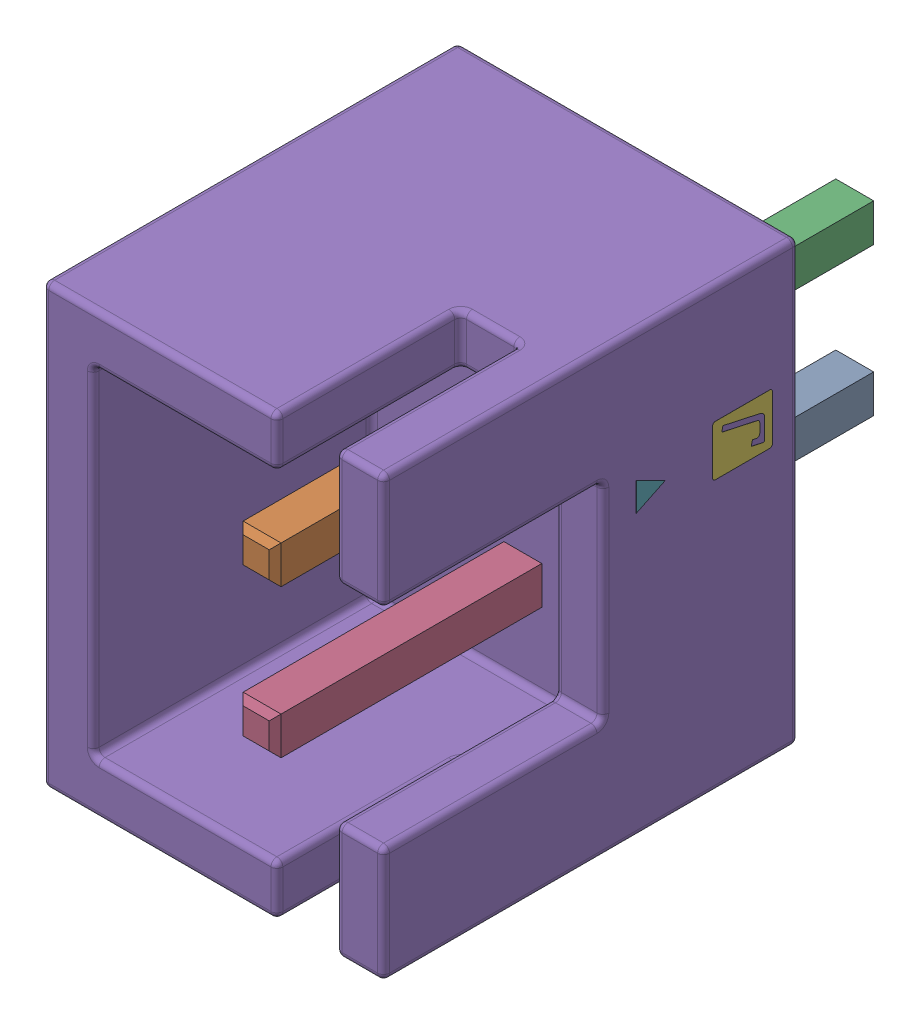
SolidWorks assembly output.step, configuration Default. Lengths in mm.
Overall size (5.75 7.4 10.4).
5 component instances, 3 part files, 0 mates.
Components (placement in the parent):
- Conn_JST_B2B-XH-A_LF_SN_eec.step-1: Conn_JST_B2B-XH-A_LF_SN_eec.step [Default] at (120.887 35.072 0) x (0 -1 0) z (0 0 1) size (7.4 5.75 10.4)
  - 1-0.step-1: 1-0.step [Default] at (0 0.025 0) x (-1 0 0) z (0 1 0) size (7.4 10.4 5.75)
    - 1-1.step-1: 1-1.step [Default] at origin size (3.14 10.2 0.64)
    - B2B-XH-A.step-1: B2B-XH-A.step [Default] at origin size (7.4 7 5.75)
    - JST_Logo_adjustable.step-1: JST_Logo_adjustable.step [Default] at (-1.7267 5.5034 2.841) size (0.85 2.3 0.01)
